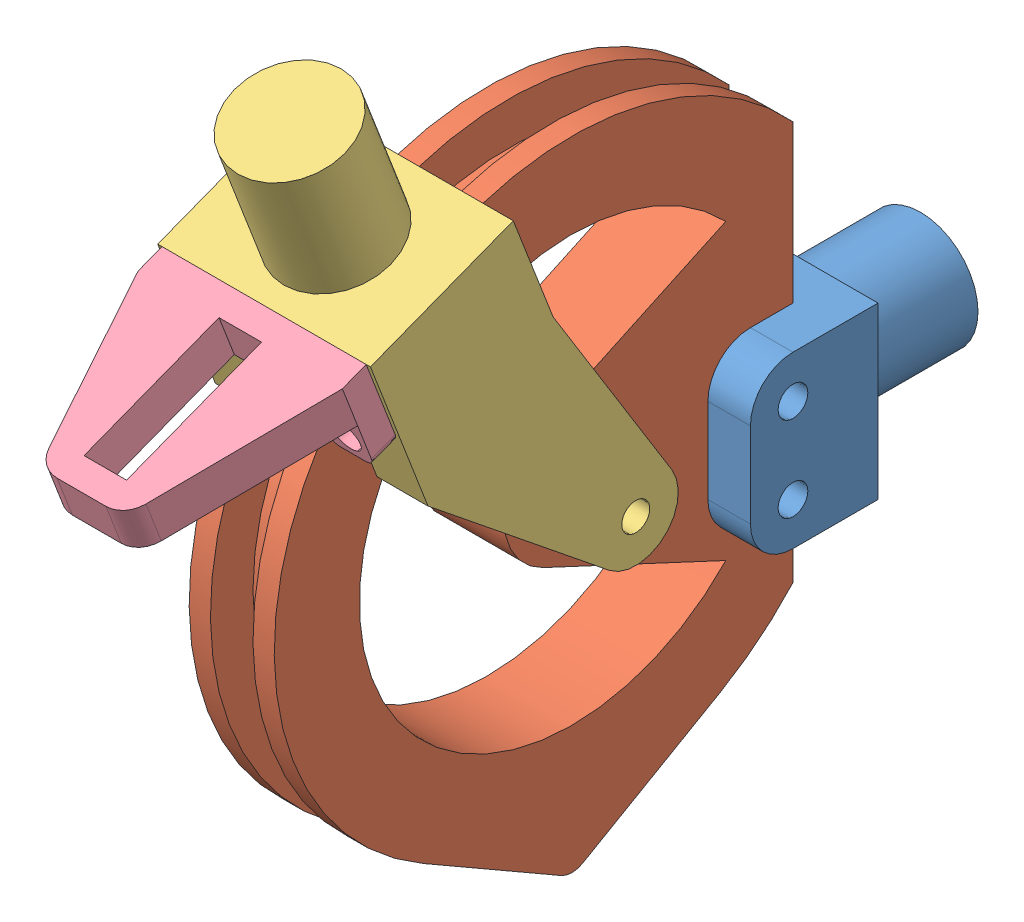
SolidWorks assembly knees, configuration ﾃﾞﾌｫﾙﾄ. Lengths in mm.
Overall size (25 93.11 98.63).
4 component instances, 4 part files, 8 mates.
Components (placement in the parent):
- knee_joint_connector-1: knee_joint_connector [ﾃﾞﾌｫﾙﾄ] at origin size (20 20 30)
- knee_joint_circle-1: knee_joint_circle [ﾃﾞﾌｫﾙﾄ] at (-5 5 30.9808) x (0 1 0) z (1 0 0) size (75 60.98 10)
- knee2-1: knee2 [ﾃﾞﾌｫﾙﾄ] at (0 53.073 59.1763) x (-1 0 0) z (0 -0.93296 -0.359979) size (25 23 60)
- knee_support-1: knee_support [ﾃﾞﾌｫﾙﾄ] at (0 28.3751 59.2934) x (-1 0 0) z (0 -0.359979 0.93296) size (24 10.5 23)
Mates (geometry in assembly coordinates):
- 同心円1: concentric aligned: cylinder of knee_joint_connector-1 through (-10 5 10) axis (1 0 0) radius 1.75; cylinder of knee_joint_circle-1 through (-5 5 10) axis (1 0 0) radius 1.75
- 同心円2: concentric aligned: cylinder of knee_joint_connector-1 through (-10 -5 10) axis (1 0 0) radius 1.75; cylinder of knee_joint_circle-1 through (-5 -5 10) axis (1 0 0) radius 1.75
- 一致1: coincident anti-aligned: plane of knee_joint_connector-1 through (5 10 15) normal (-1 0 0); plane of knee_joint_circle-1 through (5 5 30.9808) normal (1 0 0)
- 同心円3: concentric aligned: cylinder of knee_joint_circle-1 through (5 5 30.9808) axis (-1 0 0) radius 2.25; cylinder of knee2-1 through (-6.5 5 30.9808) axis (-1 0 0) radius 1.65
- 幅1: width anti-aligned: plane of knee2-1 through (-6.5 5 30.9808) normal (1 0 0); plane of knee_joint_circle-1 through (6.5 5 30.9808) normal (-1 0 0); plane of knee2-1 through (-5 5 30.9808) normal (-1 0 0); plane of knee_joint_circle-1 through (5 5 30.9808) normal (1 0 0)
- 同心円4: concentric aligned: cylinder of knee2-1 through (9.5 28.3751 59.2934) axis (0 0.359979 -0.93296) radius 1.75; cylinder of knee_support-1 through (9.5 27.2952 62.0923) axis (0 0.359979 -0.93296) radius 1.75
- 一致2: coincident anti-aligned: plane of knee2-1 through (12.5 33.0399 61.0933) normal (0 -0.359979 0.93296); plane of knee_support-1 through (0 28.3751 59.2934) normal (0 0.359979 -0.93296)
- 同心円5: concentric aligned: cylinder of knee2-1 through (-9.5 28.3751 59.2934) axis (0 0.359979 -0.93296) radius 1.75; cylinder of knee_support-1 through (-9.5 27.2952 62.0923) axis (0 0.359979 -0.93296) radius 1.75
